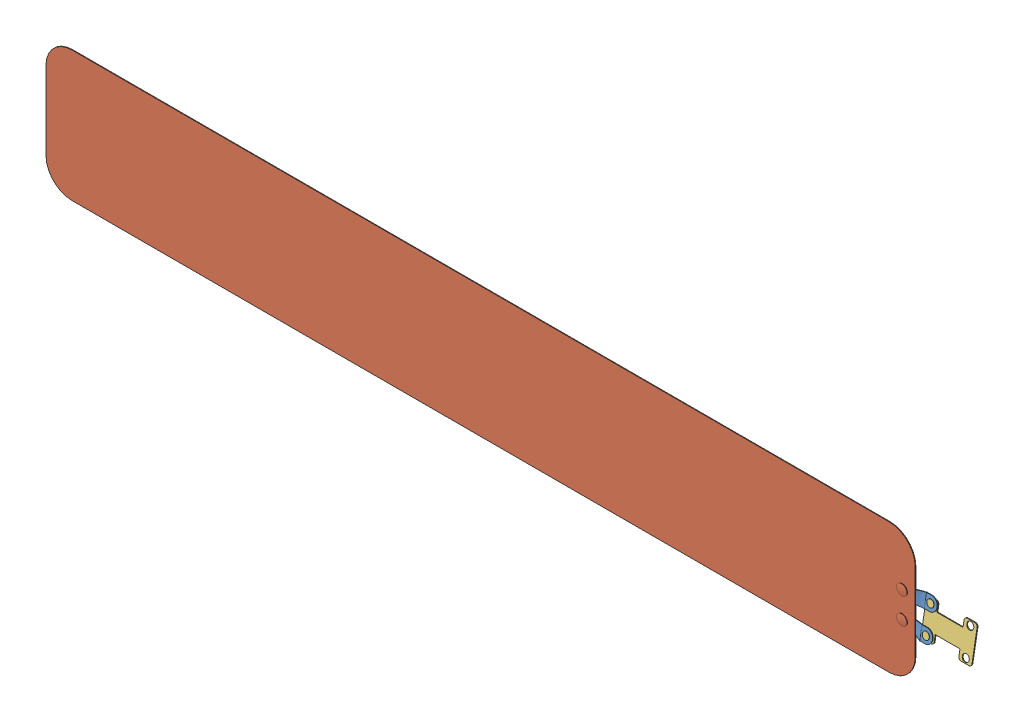
SolidWorks assembly 装配体1, configuration 默认. Lengths in mm.
Overall size (1083.32 150 18.19).
3 component instances, 3 part files, 4 mates.
Components (placement in the parent):
- 连片2-2: 连片2 [默认] at (748.0846 16.0271 -233.9182) x (1 0 0) z (0 -0.004807 0.999988) size (45 46.91 8.86)
- 扇叶-2: 扇叶 [默认] at (243.6489 1.0256 -233.2537) size (1000 150 2.96)
- 连片-1: 连片 [默认] at (840.0599 10.7885 -236.7326) x (-0.5 -0.852869 0.150384) z (0 0.173648 0.984808) size (61.68 68.45 3.01)
Mates (geometry in assembly coordinates):
- 同心2: concentric aligned: circle of 连片2-2; circle of 扇叶-2
- 同心4: concentric: circle of 连片2-2; circle of 连片-1
- 重合8: coincident: plane of 连片2-2 through (728.6489 -13.8073 -231.3803) normal (0 -0.173648 -0.984808); plane of 连片-1 through (710.9892 33.9177 -239.7955) normal (0 0.173648 0.984808)
- 同心5: concentric anti-aligned: circle of 连片2-2; circle of 连片-1
